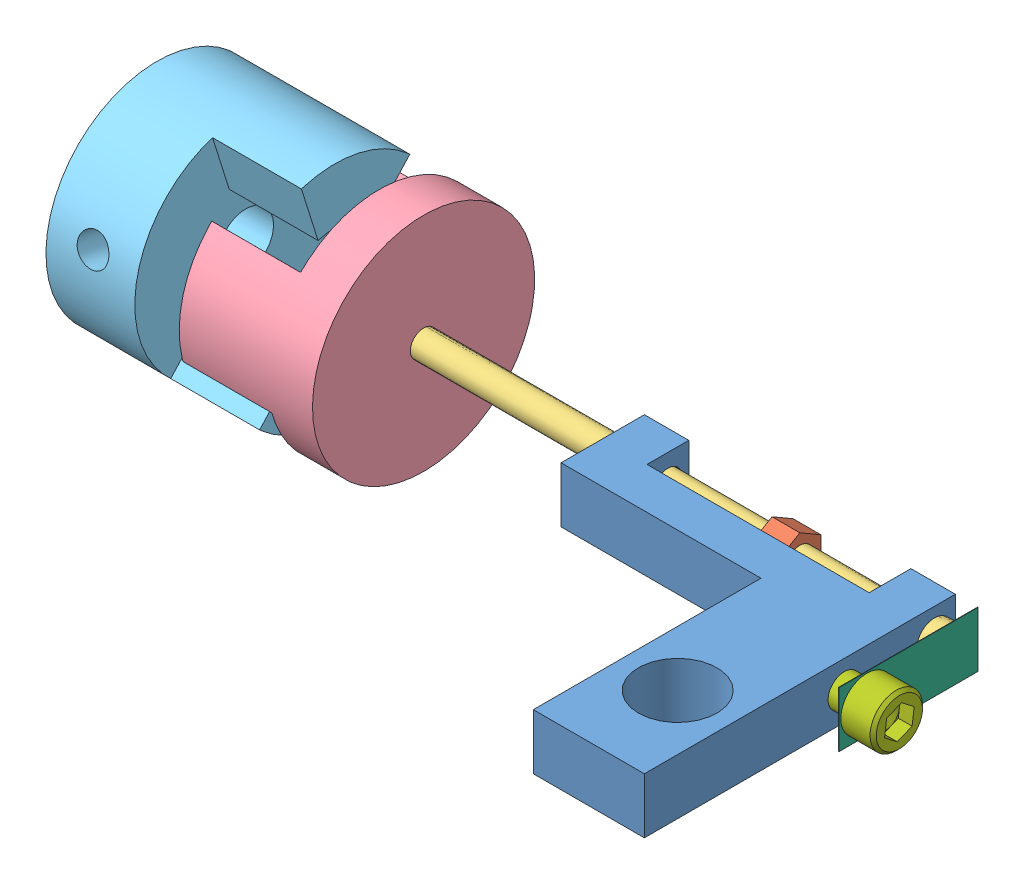
SolidWorks assembly MassAdjuster, configuration Default. Lengths in mm.
Overall size (47.6 15.55 24.36).
7 component instances, 7 part files, 13 mates.
Components (placement in the parent):
- MassAdjusterBody-1: MassAdjusterBody [Default] at (5.241 9.8269 14.0116) size (17.78 3.17 17.78)
- MassAdjusterMass-1: MassAdjusterMass [Default] at (4.8495 11.4144 6.3154) x (0 -0.985277 -0.170964) z (0 -0.170964 0.985277) size (2.72 1.59 2.59)
- MassAdjusterThreadedRod-1: MassAdjusterThreadedRod [Default] at (-17.619 11.4144 6.3154) x (0 0.946104 0.323862) z (0 0.323862 -0.946104) size (2.03 33.02 2.03)
- MassAdjusterCoupler-1: MassAdjusterCoupler [Default] at (-15.079 11.4144 6.3154) x (0 -0.966013 0.258492) z (0 -0.258492 -0.966013) size (12.7 7.62 12.7)
- MassAdjusterMotorCoupler-1: MassAdjusterMotorCoupler [Default] at (-30.319 11.4144 6.3154) x (0 -0.217449 -0.976072) z (0 -0.976072 0.217449) size (12.7 10.16 12.7)
- Spring-1: Spring [Default] at (15.4264 11.4144 9.0904) x (0 1 0) z (0 0 1) size (3.17 0.03 7.94)
- socket head cap screw_ai-1: socket head cap screw_ai [HX-SHCS 0.073-72x0.25x0.25-N] at (17.2806 11.4144 11.4716) x (-1 0 0) z (0 -0.924225 -0.381849) size (8.2 3 3)
Mates (geometry in assembly coordinates):
- Coincident3: coincident: plane of MassAdjusterBody-1 through (-1.109 9.8269 7.5092) normal (0 0 -1); plane of MassAdjusterMass-1 through (6.437 12.1037 7.5092) normal (0 0 1)
- Concentric4: concentric: circle of MassAdjusterBody-1; cylinder of MassAdjusterThreadedRod-1 through (14.131 11.4144 6.3154) axis (-1 0 0) radius 0.762
- Coincident5: coincident: plane of MassAdjusterBody-1 through (14.131 13.0019 22.9016) normal (1 0 0); plane of MassAdjusterThreadedRod-1 through (14.131 11.4144 6.3154) normal (-1 0 0)
- Concentric5: concentric: circle of MassAdjusterMass-1; cylinder of MassAdjusterThreadedRod-1 through (14.131 11.4144 6.3154) axis (-1 0 0) radius 0.762
- Concentric6: concentric: circle of MassAdjusterThreadedRod-1; circle of MassAdjusterCoupler-1
- Coincident6: coincident: plane of MassAdjusterThreadedRod-1 through (-17.619 11.4144 6.3154) normal (-1 0 0); plane of MassAdjusterCoupler-1 through (-17.619 11.4144 6.3154) normal (-1 0 0)
- Concentric7: concentric: circle of MassAdjusterCoupler-1; circle of MassAdjusterMotorCoupler-1
- Distance1: distance = 2.54 mm: plane of MassAdjusterCoupler-1 through (-17.619 11.4144 6.3154) normal (-1 0 0); plane of MassAdjusterMotorCoupler-1 through (-20.159 11.4144 6.3154) normal (1 0 0)
- Concentric8: concentric: circle of MassAdjusterBody-1; circle of Spring-1
- Coincident7: coincident: plane of MassAdjusterThreadedRod-1 through (15.401 11.4144 6.3154) normal (1 0 0); plane of Spring-1 through (15.401 11.4144 9.0904) normal (-1 0 0)
- Parallel1: parallel: line of MassAdjusterBody-1 through (14.131 13.0019 22.9016) axis (0 0 -1); line of Spring-1 through (15.4264 13.0019 13.0591) axis (0 0 -1)
- Concentric9: concentric: circle of MassAdjusterBody-1; circle of socket head cap screw_ai-1
- Coincident10: coincident: plane of Spring-1 through (15.4264 11.4144 9.0904) normal (1 0 0); plane of socket head cap screw_ai-1 through (15.4264 11.9867 10.0866) normal (-1 0 0)
